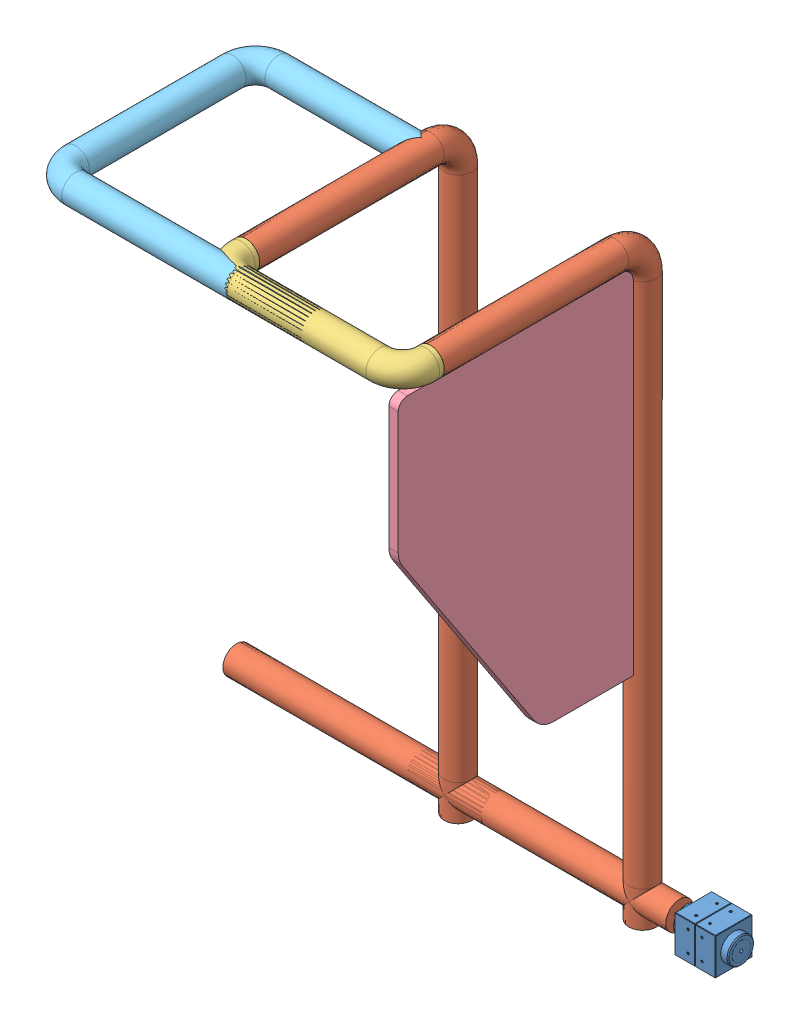
SolidWorks assembly half_seat_right, configuration Default. Lengths in mm.
Overall size (546.87 653.61 325.4).
6 component instances, 5 part files, 8 mates.
Components (placement in the parent):
- LINOS-FI-1030-35C_bulk-1: LINOS-FI-1030-35C_bulk [Default] at (36.7653 23.6083 41.7735) size (60.2 40 40)
- Part10^half_seat_right-1: Part10^half_seat_right [Default] at origin size (280 653.61 245.07) (virtual)
- Part11^half_seat_right-1: Part11^half_seat_right [Default] at (0 1077.2167 63.5471) x (1 0 0) z (0 0 -1) size (230 30 45) (virtual)
- Part10^half_seat_right-2: Part10^half_seat_right [Default] at (-200 0 0) size (280 653.61 245.07) (virtual)
- Part12^half_seat_right-1: Part12^half_seat_right [Default] at (-75 200 83.5471) x (-1 0 0) z (0 0 -1) size (24 385 320.4) (virtual)
- Part13^half_seat_right-1: Part13^half_seat_right [Default] at (0.4566 1077.2167 63.5471) x (1 0 0) z (0 0 -1) size (300 30 250) (virtual)
Mates (geometry in assembly coordinates):
- Coincident6: coincident aligned: plane of Part10^half_seat_right-1 through (-40 0 41.7735) normal (0 -1 0); plane of Part10^half_seat_right-2 through (-240 0 41.7735) normal (0 -1 0)
- Concentric1: concentric anti-aligned: cylinder of Part11^half_seat_right-1 through (-65 638.6083 301.7735) axis (-1 0 0) radius 15; cylinder of Part13^half_seat_right-1 through (-384.5434 638.6083 301.7735) axis (1 0 0) radius 15
- Parallel1: parallel aligned: cylinder of Part10^half_seat_right-2 through (-240 638.6083 71.7735) axis (0 0 -1) radius 15; cylinder of Part13^half_seat_right-1 through (-419.5434 638.6083 276.7735) axis (0 0 -1) radius 15
- Coincident7: coincident anti-aligned: plane of Part12^half_seat_right-1 through (-45 608.6083 71.7735) normal (-1 0 0)
- Tangent2: tangent anti-aligned: cylinder of Part10^half_seat_right-1 through (-40 38.6083 41.7735) axis (0 1 0) radius 15; plane of Part12^half_seat_right-1 through (-45 238.6083 56.7735) normal (0 0 -1)
- Tangent3: tangent anti-aligned: cylinder of Part10^half_seat_right-1 through (-40 638.6083 71.7735) axis (0 0 1) radius 15; plane of Part12^half_seat_right-1 through (-45 623.6083 71.7735) normal (0 1 0)
- Coincident8: coincident anti-aligned: circle of Part10^half_seat_right-2; circle of Part11^half_seat_right-1
- Coincident9: coincident aligned: circle of Part10^half_seat_right-1; circle of Part11^half_seat_right-1
